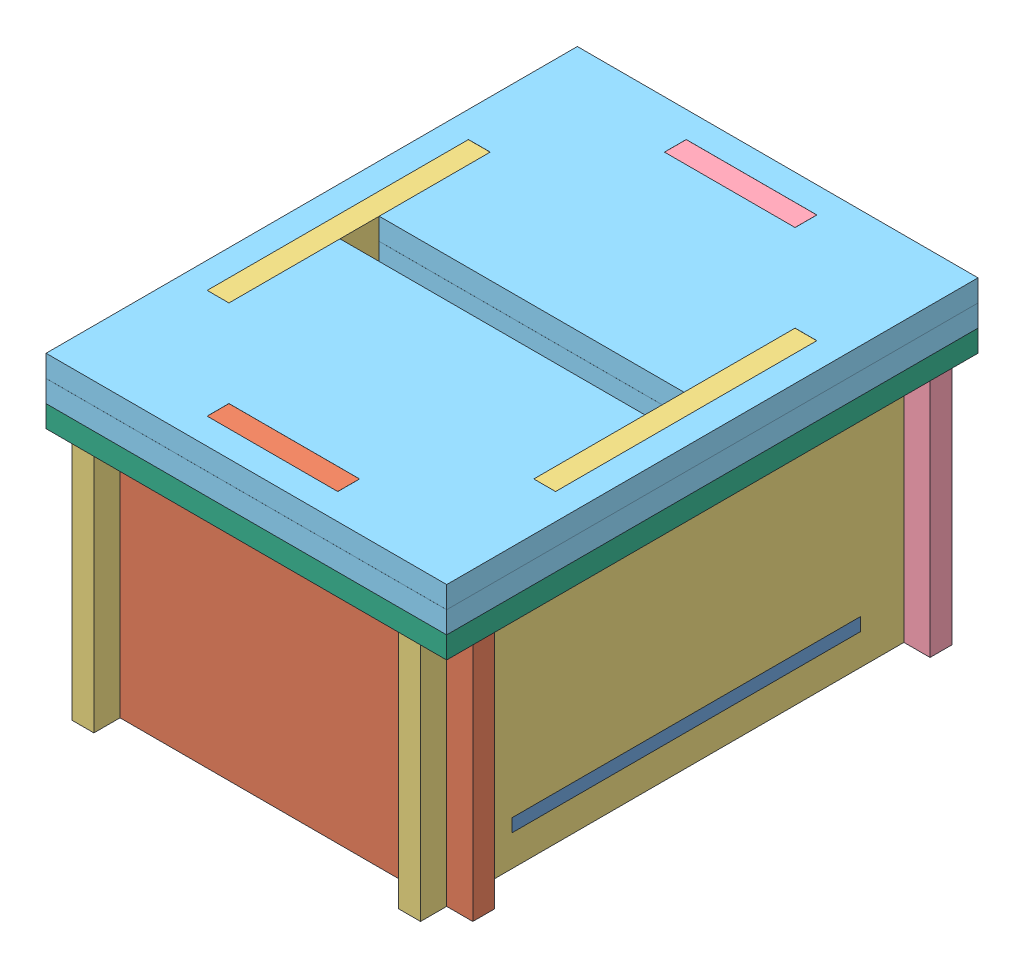
SolidWorks assembly finalAssembly, configuration Default. Lengths in mm.
Overall size (92 70 122.01).
8 component instances, 6 part files, 20 mates.
Components (placement in the parent):
- bottom-1: bottom [Default] at origin size (80 3 90)
- Front-1: Front [Default] at (0 18.8689 52.5) x (1 0 0) z (0 -1 0) size (92 5 70)
- Side-1: Side [Default] at (-40 18.8689 0) x (0 0 -1) z (0 -1 0) size (122 5 70)
- Side-2: Side [Default] at (40 18.8689 0) x (0 0 1) z (0 -1 0) size (122 5 70)
- back-1: back [Default] at (0 18.8689 -52.5) x (1 0 0) z (0 -1 0) size (92 5 70)
- top-3-1: top-3 [Default] at (0 51.3689 0) size (92 5 122)
- top-2-1: top-2 [Default] at (0 46.3689 0) size (92 5 122)
- top-3-2: top-3 [Default] at (0 56.3689 -0.01) size (92 5 122)
Mates (geometry in assembly coordinates):
- Coincident2: coincident anti-aligned: plane of bottom-1 through (0 1.5 0) normal (0 1 0); plane of Side-2 through (40 1.5 -40) normal (0 -1 0)
- Coincident3: coincident anti-aligned: plane of bottom-1 through (40 -1.5 40) normal (0 0 1); plane of Side-2 through (40 1.5 40) normal (0 0 -1)
- Coincident4: coincident anti-aligned: plane of bottom-1 through (35 -1.5 45) normal (1 0 0); plane of Side-2 through (35 18.8689 0) normal (-1 0 0)
- Coincident5: coincident anti-aligned: plane of bottom-1 through (-40 -1.5 40) normal (0 0 1); plane of Side-1 through (-40 1.5 40) normal (0 0 -1)
- Coincident6: coincident anti-aligned: plane of bottom-1 through (0 1.5 0) normal (0 1 0); plane of Side-1 through (-40 1.5 40) normal (0 -1 0)
- Coincident7: coincident anti-aligned: plane of bottom-1 through (-35 -1.5 45) normal (-1 0 0); plane of Side-1 through (-35 18.8689 0) normal (1 0 0)
- Coincident8: coincident anti-aligned: line of Front-1 through (35 18.8689 50) axis (1 0 0); line of Side-2 through (40 18.8689 50) axis (-1 0 0)
- Coincident9: coincident anti-aligned: plane of Front-1 through (0 18.8689 50) normal (0 0 -1); plane of Side-2 through (40 -8.6311 50) normal (0 0 1)
- Coincident11: coincident aligned: line of Side-1 through (-40 18.8689 -50) axis (1 0 0); line of back-1 through (-40 18.8689 -50) axis (1 0 0)
- Coincident12: coincident anti-aligned: plane of Side-1 through (-40 -8.6311 -50) normal (0 0 -1); plane of back-1 through (0 18.8689 -50) normal (0 0 1)
- Coincident13: coincident anti-aligned: plane of Front-1 through (35 46.3689 50) normal (1 0 0); plane of Side-2 through (35 18.8689 0) normal (-1 0 0)
- Coincident14: coincident anti-aligned: plane of Side-1 through (-40 18.8689 0) normal (-1 0 0); plane of back-1 through (-40 46.3689 -55) normal (1 0 0)
- Coincident15: coincident anti-aligned: plane of Side-1 through (-35 46.3689 61) normal (0 1 0); plane of top-2-1 through (0 46.3689 0) normal (0 -1 0)
- Coincident16: coincident anti-aligned: plane of Side-2 through (35 18.8689 0) normal (-1 0 0); plane of top-2-1 through (35 46.3689 -30) normal (1 0 0)
- Coincident17: coincident anti-aligned: plane of Front-1 through (0 18.8689 50) normal (0 0 -1); plane of top-2-1 through (-15 46.3689 50) normal (0 0 1)
- Coincident18: coincident anti-aligned: plane of top-3-1 through (0 51.3689 0) normal (0 -1 0); plane of top-2-1 through (0 51.3689 0) normal (0 1 0)
- Coincident19: coincident anti-aligned: plane of back-1 through (0 18.8689 -50) normal (0 0 1); plane of top-3-1 through (-15 51.3689 -50) normal (0 0 -1)
- Coincident20: coincident anti-aligned: plane of Side-1 through (-40 18.8689 0) normal (-1 0 0); plane of top-3-1 through (-40 51.3689 -30) normal (1 0 0)
- Coincident21: coincident anti-aligned: plane of top-3-1 through (0 56.3689 0) normal (0 1 0); plane of top-3-2 through (0 56.3689 -0.01) normal (0 -1 0)
- Coincident22: coincident anti-aligned: line of Side-2 through (40 61.3689 29.99) axis (0 -1 0); line of top-3-2 through (40 56.3689 29.99) axis (0 1 0)
